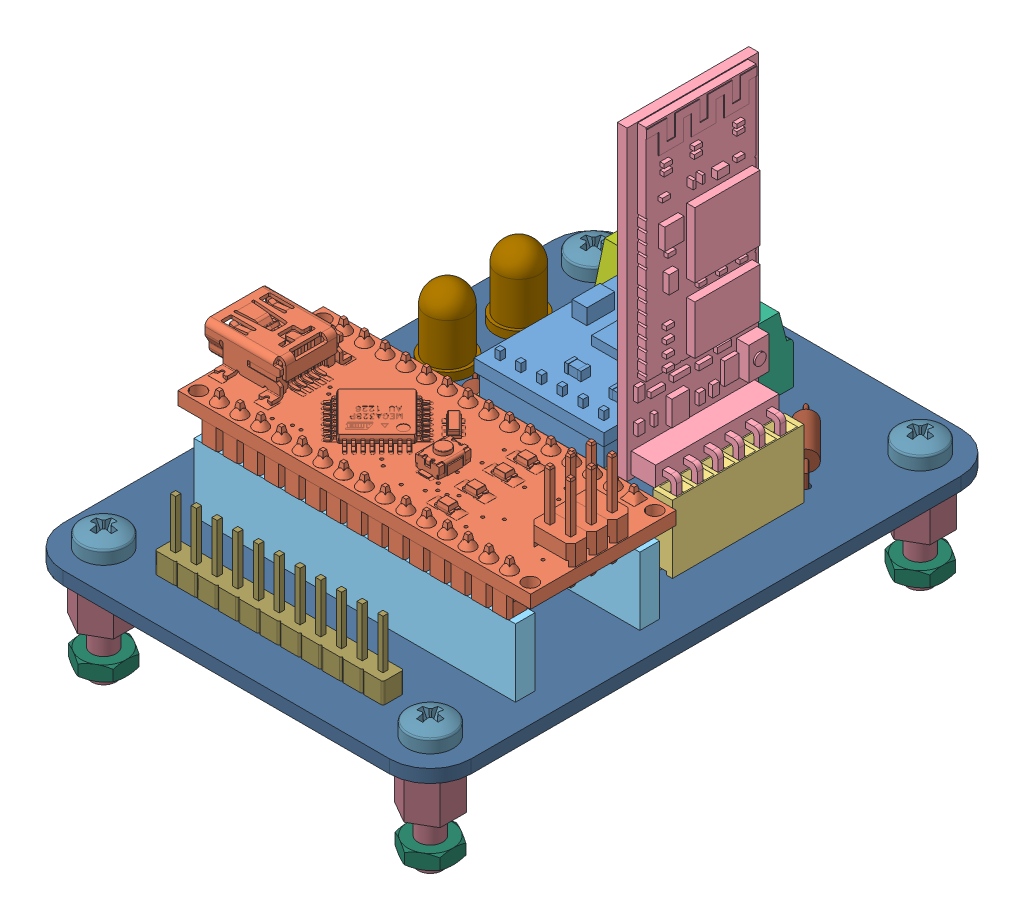
SolidWorks assembly Assembly PCB, configuration Default. Lengths in mm.
Overall size (50 58.6 70).
30 component instances, 15 part files, 60 mates.
Components (placement in the parent):
- DRV8833-1: DRV8833 [Default] at (3 14 -9.5) x (0 0 1) z (-1 0 0) size (18.4 11.9 15.9)
- Arduino Nano-1: Arduino Nano [Default] at (0.3598 23.6638 20.3801) x (-1 0 0) z (0 0 -1) size (44.95 20.74 17.81)
- Header6P-1: Header6P [Default] at (9.35 1.6 -17.1) x (-1 0 0) z (0 1 0) size (16.1 2.4 11.5)
- Header6P-2: Header6P [Default] at (9.35 1.6 -1.9) x (-1 0 0) z (0 1 0) size (16.1 2.4 11.5)
- HC-05-2: HC-05 [Varsayılan] at (11.45 46.6 -1.45) x (0 -1 0) z (1 0 0) size (42.6 16.1 5.9)
- Header6P-3: Header6P [Default] at (17 1.6 -3.15) x (0 0 -1) z (0 1 0) size (16.1 2.4 11.5)
- Header15P-1: Header15P [Default] at (-15.76 2.4 4.86) x (-1 0 0) z (0 1 0) size (39.38 2.4 11.5)
- Header15P-2: Header15P [Default] at (-15.76 2.4 20.0812) x (-1 0 0) z (0 1 0) size (39.38 2.4 11.5)
- ScrewTerminal x 4-1: ScrewTerminal x 4 [Default] at (0 1.6 -26) x (-1 0 0) z (0 0 -1) size (10.62 12 6.3)
- ScrewTerminal x 2-1: ScrewTerminal x 2 [Default] at (-10.48 1.6 -26) x (-1 0 0) z (0 0 -1) size (5.54 12 6.3)
- Push button-1: Push button [Default] at (-18.25 1.6 -2.35) x (0 0 1) z (-1 0 0) size (7.14 7.7 6)
- Led-1: Led [Default] at (-18.5 1.6 -19.33) x (0 0 1) z (-1 0 0) size (5.8 11.9 5.8)
- PCB 50 x 70-3: PCB 50 x 70 [Default] at origin size (50 1.6 70)
- Led-2: Led [Default] at (-18.5 1.6 -10.59) x (0 0 1) z (-1 0 0) size (5.8 11.9 5.8)
- Weerstand-1: Weerstand [Default] at (-10.4645 1.6 -14.4645) x (0.707107 0 -0.707107) z (0.707107 0 0.707107) size (2.5 5.7 10.5)
- Weerstand-2: Weerstand [Default] at (-10.4645 1.6 -5.9645) x (0.707107 0 -0.707107) z (0.707107 0 0.707107) size (2.5 5.7 10.5)
- Weerstand-3: Weerstand [Default] at (13.0355 1.6 -22.9645) x (0.707107 0 -0.707107) z (0.707107 0 0.707107) size (2.5 5.7 10.5)
- Header11P-1: Header11P [Default] at (0 1.6 28.5) size (27.94 11.74 2.54)
- M3 spacer 6 mm-1: M3 spacer 6 mm [Default] at (20 -6 -30) size (5.6 12 6.47)
- M3 spacer 6 mm-2: M3 spacer 6 mm [Default] at (-20 -6 -30) x (0.5 0 0.866025) z (-0.866025 0 0.5) size (5.6 12 6.47)
- M3 spacer 6 mm-3: M3 spacer 6 mm [Default] at (-20 -6 30) x (0.5 0 0.866025) z (-0.866025 0 0.5) size (5.6 12 6.47)
- M3 spacer 6 mm-4: M3 spacer 6 mm [Default] at (20 -6 30) size (5.6 12 6.47)
- pan head cross recess screw_iso-1: pan head cross recess screw_iso [ISO 7045 - M3 x 5 - Z - 5N] at (20 4 30) x (0 -1 0) z (0 0 1) size (7.35 5.6 5.6)
- pan head cross recess screw_iso-2: pan head cross recess screw_iso [ISO 7045 - M3 x 5 - Z - 5N] at (20 4 -30) x (0 -1 0) z (0 0 1) size (7.35 5.6 5.6)
- pan head cross recess screw_iso-3: pan head cross recess screw_iso [ISO 7045 - M3 x 5 - Z - 5N] at (-20 4 30) x (0 -1 0) z (0 0 1) size (7.35 5.6 5.6)
- pan head cross recess screw_iso-4: pan head cross recess screw_iso [ISO 7045 - M3 x 5 - Z - 5N] at (-20 4 -30) x (0 -1 0) z (0 0 1) size (7.35 5.6 5.6)
- hex thin nut chamfered gradeab_iso-1: hex thin nut chamfered gradeab_iso [ISO - 4035 - M3 - N] at (20 -10.8 -30) x (1 0 0) z (0 -1 0) size (5.5 6.35 1.8)
- hex thin nut chamfered gradeab_iso-2: hex thin nut chamfered gradeab_iso [ISO - 4035 - M3 - N] at (20 -10.8 30) x (1 0 0) z (0 -1 0) size (5.5 6.35 1.8)
- hex thin nut chamfered gradeab_iso-3: hex thin nut chamfered gradeab_iso [ISO - 4035 - M3 - N] at (-20 -10.8 30) x (0.5 0 -0.866025) z (0 -1 0) size (5.5 6.35 1.8)
- hex thin nut chamfered gradeab_iso-4: hex thin nut chamfered gradeab_iso [ISO - 4035 - M3 - N] at (-20 -10.8 -30) x (1 0 0) z (0 -1 0) size (5.5 6.35 1.8)
Mates (geometry in assembly coordinates):
- ProfileCenter6: profile center = 5.6 mm aligned: plane of DRV8833-1 through (3 4 -9.5) normal (0 -1 0); plane of Header6P-1 through (-3.525 -1.6 -17.1) normal (0 -1 0)
- ProfileCenter7: profile center = 5.6 mm aligned: plane of Header6P-2 through (-3.525 -1.6 -1.9) normal (0 -1 0); plane of DRV8833-1 through (3 4 -9.5) normal (0 -1 0)
- ProfileCenter9: profile center = 5.6 mm aligned: plane of HC-05-2 through (11.45 4 -1.45) normal (0 -1 0); plane of Header6P-3 through (17 -1.6 -16.025) normal (0 -1 0)
- ProfileCenter10: profile center = 3.5 mm aligned: plane of Header15P-1 through (-15.76 -1.6 4.86) normal (0 -1 0); plane of Arduino Nano-1 through (-15.76 1.9 4.86) normal (0 -1 0)
- ProfileCenter11: profile center = 3.5 mm aligned: plane of Header15P-2 through (-15.76 -1.6 20.0812) normal (0 -1 0); plane of Arduino Nano-1 through (-15.76 1.9 20.0812) normal (0 -1 0)
- Coincident2: coincident aligned: plane of PCB 50 x 70-3 through (0 0 0) normal (0 1 0)
- Coincident3: coincident aligned: plane of PCB 50 x 70-3 through (0 0 0) normal (0 0 1)
- Coincident4: coincident aligned: plane of PCB 50 x 70-3 through (0 0 0) normal (1 0 0)
- ProfileCenter12: profile center = 3.2 mm anti-aligned: plane of Header15P-1 through (-15.76 -1.6 4.86) normal (0 -1 0); circle of PCB 50 x 70-3
- Parallel5: parallel aligned: plane of Header15P-2 through (-14.49 9.1 21.2812) normal (0 0 1); plane of PCB 50 x 70-3 through (-25 1.6 35) normal (0 0 1)
- ProfileCenter14: profile center = 3.2 mm anti-aligned: plane of Header6P-3 through (17 -1.6 -3.325) normal (0 -1 0); circle of PCB 50 x 70-3
- Parallel6: parallel aligned: plane of Header6P-3 through (18.2 1.6 -1.65) normal (1 0 0); plane of PCB 50 x 70-3 through (25 1.6 35) normal (1 0 0)
- ProfileCenter15: profile center = 3.2 mm anti-aligned: circle of PCB 50 x 70-3; plane of Header6P-1 through (-3.525 -1.6 -17.1) normal (0 -1 0)
- Parallel7: parallel aligned: plane of Header6P-1 through (10.85 1.6 -18.3) normal (0 0 -1); plane of PCB 50 x 70-3 through (-25 1.6 -35) normal (0 0 -1)
- ProfileCenter16: profile center = 3.2 mm anti-aligned: plane of ScrewTerminal x 4-1 through (0 -1.6 -26) normal (0 -1 0); circle of PCB 50 x 70-3
- Parallel9: parallel aligned: plane of ScrewTerminal x 4-1 through (5.31 10.4 -29.15) normal (1 0 0); plane of PCB 50 x 70-3 through (25 1.6 35) normal (1 0 0)
- ProfileCenter17: profile center = 3.2 mm anti-aligned: plane of ScrewTerminal x 2-1 through (-10.48 -1.6 -26) normal (0 -1 0); circle of PCB 50 x 70-3
- Parallel10: parallel aligned: plane of ScrewTerminal x 2-1 through (-13.25 10.4 -29.15) normal (-1 0 0); plane of PCB 50 x 70-3 through (-25 1.6 35) normal (-1 0 0)
- ProfileCenter18: profile center = 3.2 mm aligned: plane of Led-2 through (-18.5 -1.6 -11.86) normal (0 -1 0); circle of PCB 50 x 70-3
- ProfileCenter19: profile center = 3.2 mm aligned: plane of Led-1 through (-18.5 -1.6 -20.6) normal (0 -1 0); circle of PCB 50 x 70-3
- Coincident12: coincident aligned: plane of Led-1 through (-18.5 1.6 -19.33) normal (-1 0 0); plane of Led-2 through (-18.5 1.6 -10.59) normal (-1 0 0)
- ProfileCenter20: profile center = 3.2 mm anti-aligned: plane of Push button-1 through (-18.25 -1.6 -2.35) normal (0 -1 0); circle of PCB 50 x 70-3
- Parallel12: parallel aligned: plane of Push button-1 through (-21.25 4.6 -5.35) normal (-1 0 0); plane of PCB 50 x 70-3 through (-25 1.6 35) normal (-1 0 0)
- ProfileCenter22: profile center = 3.2 mm aligned: plane of Weerstand-1 through (-14 -1.6 -18) normal (0 -1 0); circle of PCB 50 x 70-3
- ProfileCenter23: profile center = 3.2 mm aligned: plane of Weerstand-2 through (-14 -1.6 -9.5) normal (0 -1 0); circle of PCB 50 x 70-3
- ProfileCenter24: profile center = 3.2 mm aligned: plane of Weerstand-3 through (9.5 -1.6 -26.5) normal (0 -1 0); circle of PCB 50 x 70-3
- Parallel14: parallel aligned: plane of Weerstand-1 through (-10.4645 1.6 -14.4645) normal (0.707107 0 -0.707107); plane of Weerstand-2 through (-10.4645 1.6 -5.9645) normal (0.707107 0 -0.707107)
- Parallel15: parallel aligned: plane of Weerstand-2 through (-10.4645 1.6 -5.9645) normal (0.707107 0 -0.707107); plane of Weerstand-3 through (13.0355 1.6 -22.9645) normal (0.707107 0 -0.707107)
- Angle1: planar angle = 0.785398 rad aligned: plane of Weerstand-1 through (-10.4645 1.6 -14.4645) normal (0.707107 0 -0.707107)
- Coincident13: coincident aligned: plane of M3 spacer 6 mm-1 through (20 0 -30) normal (0 1 0); plane of M3 spacer 6 mm-2 through (-20 0 -30) normal (0 1 0)
- Coincident14: coincident aligned: plane of M3 spacer 6 mm-3 through (-20 0 30) normal (0 1 0); plane of M3 spacer 6 mm-4 through (20 0 30) normal (0 1 0)
- Coincident15: coincident aligned: plane of M3 spacer 6 mm-2 through (-20 0 -30) normal (0 1 0); plane of M3 spacer 6 mm-3 through (-20 0 30) normal (0 1 0)
- Concentric1: concentric aligned: cylinder of PCB 50 x 70-3 through (-20 -4.5255 30) axis (0 1 0) radius 1.6; cylinder of M3 spacer 6 mm-3 through (-20 -4 30) axis (0 1 0) radius 1.5
- Concentric2: concentric aligned: cylinder of PCB 50 x 70-3 through (20 -4.5255 30) axis (0 1 0) radius 1.6; cylinder of M3 spacer 6 mm-4 through (20 -4 30) axis (0 1 0) radius 1.5
- Concentric3: concentric aligned: cylinder of PCB 50 x 70-3 through (-20 -4.5255 -30) axis (0 1 0) radius 1.6; cylinder of M3 spacer 6 mm-2 through (-20 -4 -30) axis (0 1 0) radius 1.5
- Concentric4: concentric aligned: cylinder of PCB 50 x 70-3 through (20 -4.5255 -30) axis (0 1 0) radius 1.6; cylinder of M3 spacer 6 mm-1 through (20 -4 -30) axis (0 1 0) radius 1.5
- Coincident16: coincident aligned: plane of M3 spacer 6 mm-2 through (-22.8 0 -31.6166) normal (-1 0 0); plane of M3 spacer 6 mm-3 through (-22.8 0 28.3834) normal (-1 0 0)
- Coincident17: coincident aligned: plane of M3 spacer 6 mm-1 through (17.2 0 -31.6166) normal (-1 0 0); plane of M3 spacer 6 mm-4 through (17.2 0 28.3834) normal (-1 0 0)
- Coincident19: coincident anti-aligned: plane of PCB 50 x 70-3 through (0 0 0) normal (0 -1 0); plane of M3 spacer 6 mm-3 through (-20 0 30) normal (0 1 0)
- Coincident21: coincident aligned: plane of pan head cross recess screw_iso-1 through (21.5 1.6 30) normal (0 -1 0); plane of pan head cross recess screw_iso-4 through (-18.5 1.6 -30) normal (0 -1 0)
- Coincident22: coincident aligned: plane of pan head cross recess screw_iso-2 through (21.5 1.6 -30) normal (0 -1 0); plane of pan head cross recess screw_iso-4 through (-18.5 1.6 -30) normal (0 -1 0)
- Coincident23: coincident aligned: plane of pan head cross recess screw_iso-2 through (21.5 1.6 -30) normal (0 -1 0); plane of pan head cross recess screw_iso-3 through (-18.5 1.6 30) normal (0 -1 0)
- Coincident24: coincident anti-aligned: plane of PCB 50 x 70-3 through (0 1.6 0) normal (0 1 0); plane of pan head cross recess screw_iso-3 through (-18.5 1.6 30) normal (0 -1 0)
- Concentric5: concentric aligned: cylinder of PCB 50 x 70-3 through (-20 -4.5255 30) axis (0 1 0) radius 1.6; cylinder of pan head cross recess screw_iso-3 through (-20 29.4 30) axis (0 1 0) radius 1.5
- Concentric6: concentric aligned: cylinder of PCB 50 x 70-3 through (-20 -4.5255 -30) axis (0 1 0) radius 1.6; cylinder of pan head cross recess screw_iso-4 through (-20 29.4 -30) axis (0 1 0) radius 1.5
- Concentric7: concentric aligned: cylinder of PCB 50 x 70-3 through (20 -4.5255 30) axis (0 1 0) radius 1.6; cylinder of pan head cross recess screw_iso-1 through (20 29.4 30) axis (0 1 0) radius 1.5
- Concentric8: concentric aligned: cylinder of PCB 50 x 70-3 through (20 -4.5255 -30) axis (0 1 0) radius 1.6; cylinder of pan head cross recess screw_iso-2 through (20 29.4 -30) axis (0 1 0) radius 1.5
- Coincident25: coincident aligned: plane of pan head cross recess screw_iso-3 through (-19.63 2.25 30.5275) normal (-1 0 0); plane of pan head cross recess screw_iso-4 through (-19.63 2.25 -29.4725) normal (-1 0 0)
- Coincident26: coincident aligned: plane of pan head cross recess screw_iso-1 through (20.37 2.25 30.5275) normal (-1 0 0); plane of pan head cross recess screw_iso-2 through (20.37 2.25 -29.4725) normal (-1 0 0)
- Coincident28: coincident aligned: plane of hex thin nut chamfered gradeab_iso-2 through (20 -10.8 33.1754) normal (0 -1 0); plane of hex thin nut chamfered gradeab_iso-4 through (-20 -10.8 -26.8246) normal (0 -1 0)
- Coincident29: coincident aligned: plane of hex thin nut chamfered gradeab_iso-1 through (20 -10.8 -26.8246) normal (0 -1 0); plane of hex thin nut chamfered gradeab_iso-2 through (20 -10.8 33.1754) normal (0 -1 0)
- Coincident30: coincident aligned: plane of hex thin nut chamfered gradeab_iso-1 through (20 -10.8 -26.8246) normal (0 -1 0); plane of hex thin nut chamfered gradeab_iso-3 through (-17.25 -10.8 31.5877) normal (0 -1 0)
- Concentric9: concentric anti-aligned: cylinder of M3 spacer 6 mm-3 through (-20 -12 30) axis (0 1 0) radius 1.5; cylinder of hex thin nut chamfered gradeab_iso-3 through (-20 -9 30) axis (0 -1 0) radius 1.25
- Concentric10: concentric anti-aligned: cylinder of M3 spacer 6 mm-2 through (-20 -12 -30) axis (0 1 0) radius 1.5; cylinder of hex thin nut chamfered gradeab_iso-4 through (-20 -9 -30) axis (0 -1 0) radius 1.25
- Concentric11: concentric anti-aligned: cylinder of M3 spacer 6 mm-4 through (20 -12 30) axis (0 1 0) radius 1.5; cylinder of hex thin nut chamfered gradeab_iso-2 through (20 -9 30) axis (0 -1 0) radius 1.25
- Concentric12: concentric anti-aligned: cylinder of M3 spacer 6 mm-1 through (20 -12 -30) axis (0 1 0) radius 1.5; cylinder of hex thin nut chamfered gradeab_iso-1 through (20 -9 -30) axis (0 -1 0) radius 1.25
- Coincident32: coincident aligned: plane of hex thin nut chamfered gradeab_iso-3 through (-22.75 -9 31.5877) normal (-1 0 0); plane of hex thin nut chamfered gradeab_iso-4 through (-22.75 -9 -28.4123) normal (-1 0 0)
- Coincident33: coincident aligned: plane of hex thin nut chamfered gradeab_iso-1 through (17.25 -9 -28.4123) normal (-1 0 0); plane of hex thin nut chamfered gradeab_iso-2 through (17.25 -9 31.5877) normal (-1 0 0)
- Distance1: distance = 3 mm anti-aligned: plane of hex thin nut chamfered gradeab_iso-3 through (-17.25 -9 31.5877) normal (0 1 0); plane of M3 spacer 6 mm-3 through (-20 -6 30) normal (0 -1 0)
- ProfileCenter28: profile center = 3.2 mm anti-aligned: plane of Header11P-1 through (0 -1.6 28.5) normal (0 -1 0); circle of PCB 50 x 70-3
